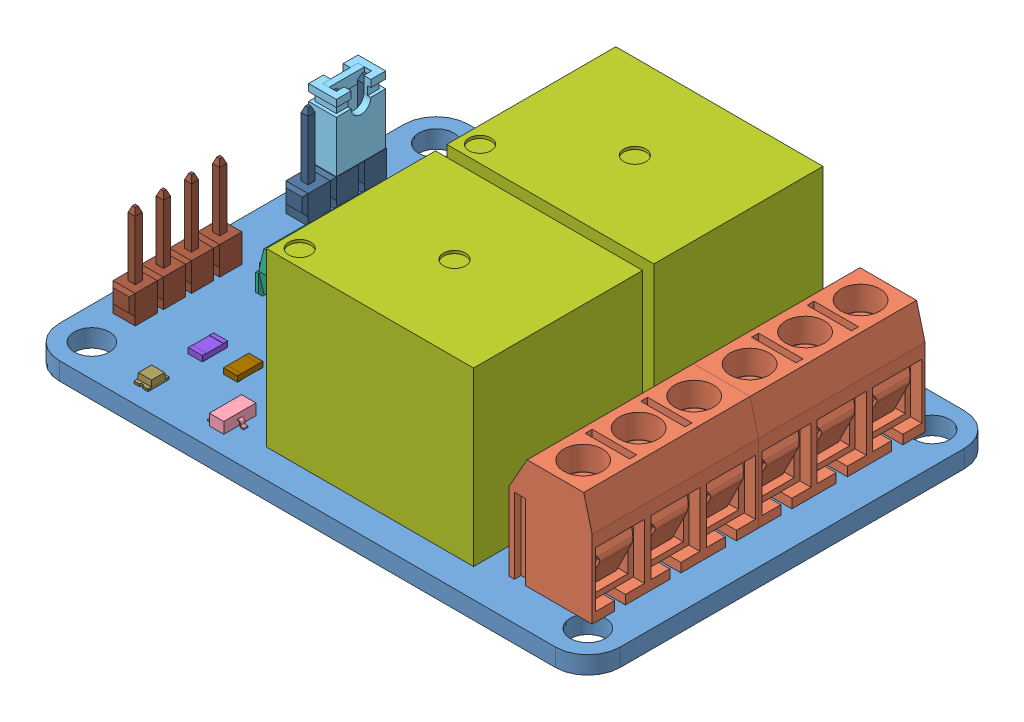
SolidWorks assembly RelayBoard, configuration Default. Lengths in mm.
Overall size (50.55 19.3 36.88).
20 component instances, 12 part files, 0 mates.
Components (placement in the parent):
- RelayBase-1: RelayBase [Default] at origin size (50.55 1.6 36.88)
- Terminator-1: Terminator [Default] at (18.925 1.6002 -12.5) x (0 0 -1) z (1 0 0) size (15.6 13.4 7.5)
- Terminator-2: Terminator [Default] at (18.925 1.6002 2.5) x (0 0 -1) z (1 0 0) size (15.6 13.4 7.5)
- D1-1: D1 [Default] at (-9.4615 2.2352 -8.9789) x (0 0 1) z (-1 0 0) size (3.3 1.27 1.27)
- sot-23-j3y-1: sot-23-j3y [Default] at (-9.8275 2.1202 -15.1489) x (0 0 -1) z (1 0 0) size (2.9 1.02 2.35)
- Jumper-1: Jumper [Default] at (-22.937 10.1727 -8.0805) x (0 0 1) z (-1 0 0) size (4.45 6.03 2.49)
- PC-817-1: PC-817 [Default] at (-14.5512 4.1502 -2.5369) size (7.88 7 4.58)
- Relay-1: Relay [Default] at (3.048 1.6002 -8.0264) x (-1 0 0) z (0 0 -1) size (18.67 18.49 15.24)
- smdres_102-1: smdres_102 [Default] at (-15.8115 1.6002 -10.7569) x (0 0 1) z (-1 0 0) size (2.29 0.5 1.27)
- smdres_115-1: smdres_115 [Default] at (-12.6365 1.6002 -10.7569) x (0 0 1) z (-1 0 0) size (2.29 0.5 1.27)
- BreakAwayHeaders_3PinShort-1: BreakAwayHeaders_3PinShort [Default] at (-22.6474 2.8702 -4.2705) x (0 0 1) z (-1 0 0) size (7.62 12.19 2)
- BreakAwayHeaders_4PinShort-1: BreakAwayHeaders_4PinShort [Default] at (-22.6474 2.8702 3.6985) x (0 0 -1) z (1 0 0) size (10.16 12.19 2)
- smallled_SmallRelay-1: smallled_SmallRelay [Default] at (-16.5735 1.8002 -15.7124) x (0 0 1) z (-1 0 0) size (1.9 0.7 1.27)
- Relay-2: Relay [Default] at (3.048 1.6002 8.2296) x (-1 0 0) z (0 0 -1) size (18.67 18.49 15.24)
- D1-2: D1 [Default] at (-9.4615 2.2352 9.1821) x (0 0 -1) z (1 0 0) size (3.3 1.27 1.27)
- sot-23-j3y-2: sot-23-j3y [Default] at (-9.8275 2.1202 15.3521) x (0 0 -1) z (1 0 0) size (2.9 1.02 2.35)
- PC-817-2: PC-817 [Default] at (-14.5512 4.1502 2.7401) size (7.88 7 4.58)
- smallled_SmallRelay-2: smallled_SmallRelay [Default] at (-16.5735 1.8002 15.9156) x (0 0 1) z (-1 0 0) size (1.9 0.7 1.27)
- smdres_102-2: smdres_102 [Default] at (-15.8115 1.6002 10.9601) x (0 0 1) z (-1 0 0) size (2.29 0.5 1.27)
- smdres_115-2: smdres_115 [Default] at (-12.6365 2.1002 10.9601) x (0 0 -1) z (-1 0 0) size (2.29 0.5 1.27)
